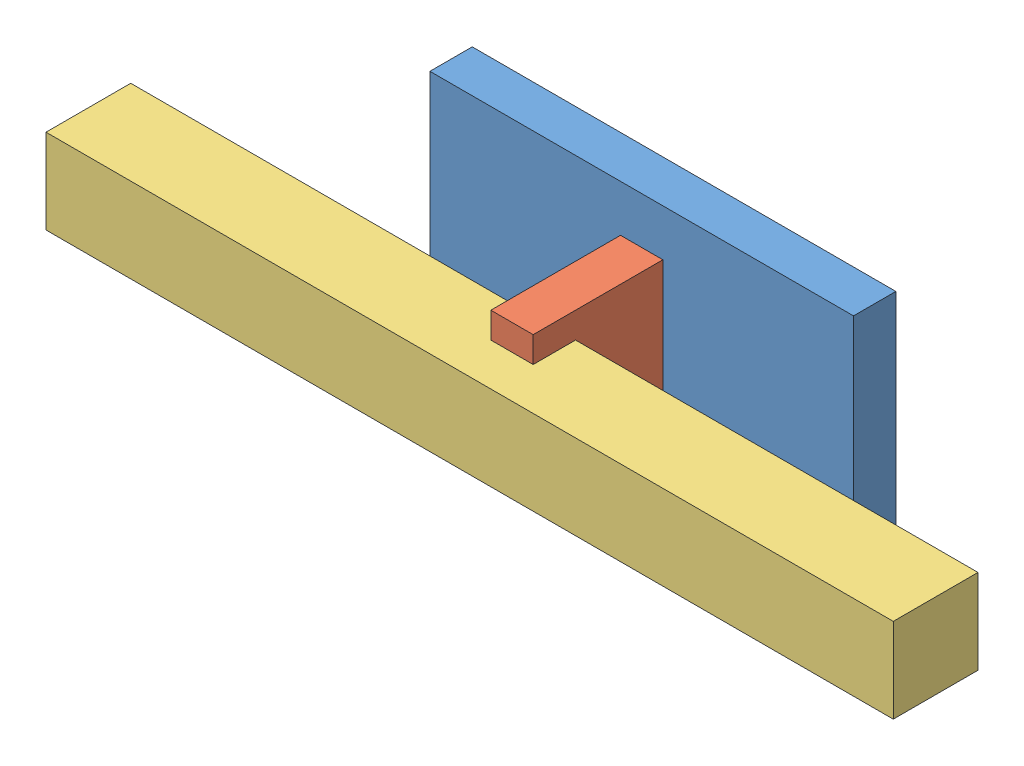
SolidWorks assembly Baugruppe1, configuration Standard. Lengths in mm.
Overall size (200 50 50.62).
3 component instances, 3 part files, 6 mates.
Components (placement in the parent):
- v-01-1: v-01 [Standard] at (-61.3509 29.0658 -5) size (100 50 10)
- Platte-1: Platte [Standard] at (-6.3509 18.0357 5) x (0 0 1) z (-1 0 0) size (30.62 27.94 10)
- Stange-1: Stange [Standard] at (-111.3509 11.9253 25.6158) x (0 -1 0) z (0 0 1) size (20 200 20)
Mates (geometry in assembly coordinates):
- Deckungsgleich1: coincident: plane of v-01-1 through (-61.3509 29.0658 5) normal (0 0 1); plane of Platte-1 through (-16.3509 18.0357 5) normal (0 0 -1)
- Breite1: width: plane of v-01-1 through (-61.3509 29.0658 5) normal (-1 0 0); plane of Platte-1 through (38.6491 29.0658 5) normal (1 0 0); plane of v-01-1 through (-16.3509 18.0357 5) normal (-1 0 0); plane of Platte-1 through (-6.3509 18.0357 5) normal (1 0 0)
- Breite2: width aligned: plane of v-01-1 through (-61.3509 29.0658 5) normal (0 1 0); plane of Platte-1 through (-61.3509 -20.9342 5) normal (0 -1 0); plane of v-01-1 through (-16.3509 18.0357 5) normal (0 1 0); plane of Platte-1 through (-16.3509 -9.9042 5) normal (0 -1 0)
- Deckungsgleich2: coincident: plane of Platte-1 through (-16.3509 11.9253 35.6158) normal (0 -1 0); plane of Stange-1 through (41.2193 11.9253 25.6158) normal (0 1 0)
- Deckungsgleich3: coincident: plane of Platte-1 through (-16.3509 18.0357 25.6158) normal (0 0 1); plane of Stange-1 through (41.2193 11.9253 25.6158) normal (0 0 -1)
- Breite3: width aligned: plane of Stange-1 through (88.6491 11.9253 25.6158) normal (1 0 0); plane of Platte-1 through (-111.3509 11.9253 25.6158) normal (-1 0 0); plane of Stange-1 through (-6.3509 18.0357 5) normal (1 0 0); plane of Platte-1 through (-16.3509 18.0357 5) normal (-1 0 0)
